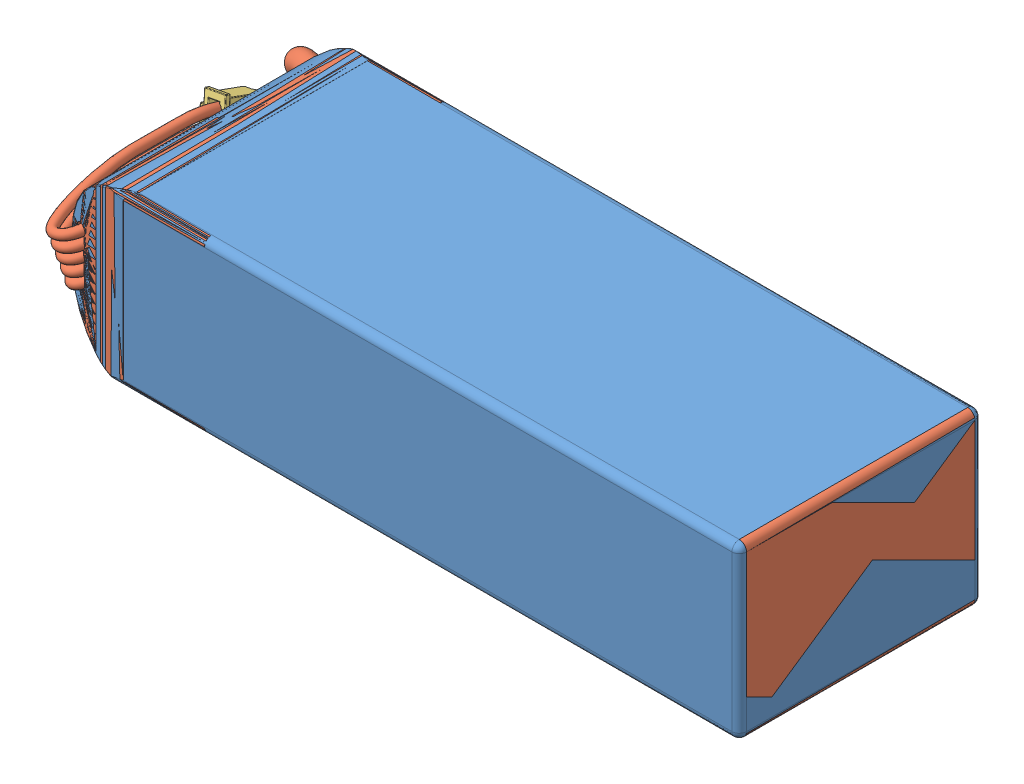
SolidWorks assembly Bateria Lipo, configuration Predeterminado. Lengths in mm.
Overall size (148.26 35.01 60.86).
4 component instances, 4 part files, 7 mates.
Components (placement in the parent):
- Funda de la bateria-1: Funda de la bateria [Predeterminado] at (-13.4133 -21.9262 140) size (140 35.01 50.88)
- Nucleo de la bateria-1: Nucleo de la bateria [Predeterminado] at (-13.4133 -21.9262 140) size (145.58 35 59.73)
- Conector-1: Conector [Predeterminado] at (-85.2332 -3.172 127.131) x (-0.20539 0.937139 -0.282108) z (-0.13236 0.259007 0.956764) size (14.8 5.7 7.75)
- Conector XT60-1: Conector XT60 [Predeterminado] at (18.8662 -3.823 110.2533) x (0 -1 0) z (-1 0 0) size (15.6 8 21.81)
Mates (geometry in assembly coordinates):
- Coincidente1: coincident: line of Funda de la bateria-1 through (-83.4133 -21.9262 165) axis (1 0 0); line of Nucleo de la bateria-1 through (-83.4133 -21.9262 165) axis (1 0 0)
- Coincidente2: coincident: line of Funda de la bateria-1 through (56.5867 -21.9262 165) axis (0 0 -1); line of Nucleo de la bateria-1 through (56.5867 -21.9262 165) axis (0 0 -1)
- Coincidente9: coincident: line of Nucleo de la bateria-1 through (-87.4639 -0.5879 123.4309) axis (0.20539 -0.937139 0.282108); line of Conector-1 through (-85.4544 -9.7569 126.1911) axis (-0.20539 0.937139 -0.282108)
- Bloquear1: lock: unknown of Nucleo de la bateria-1; unknown of Conector-1
- Concéntrica1: concentric: cylinder of Nucleo de la bateria-1 through (10.7799 -8.1863 110.0567) axis (-1 0 0) radius 2.8657; cylinder of Conector XT60-1 through (14.8662 -8.1863 110.0567) axis (1 0 0) radius 3
- Concéntrica2: concentric: cylinder of Nucleo de la bateria-1 through (10.7798 -0.5863 110.0567) axis (-1 0 0) radius 2.8657; cylinder of Conector XT60-1 through (14.8662 -0.5863 110.0567) axis (1 0 0) radius 3
- Coincidente10: coincident: plane of ? through (18.8662 -0.5863 112.9224) normal (1 0 0); plane of Conector XT60-1 through (18.8662 -3.823 110.2533) normal (-1 0 0)
